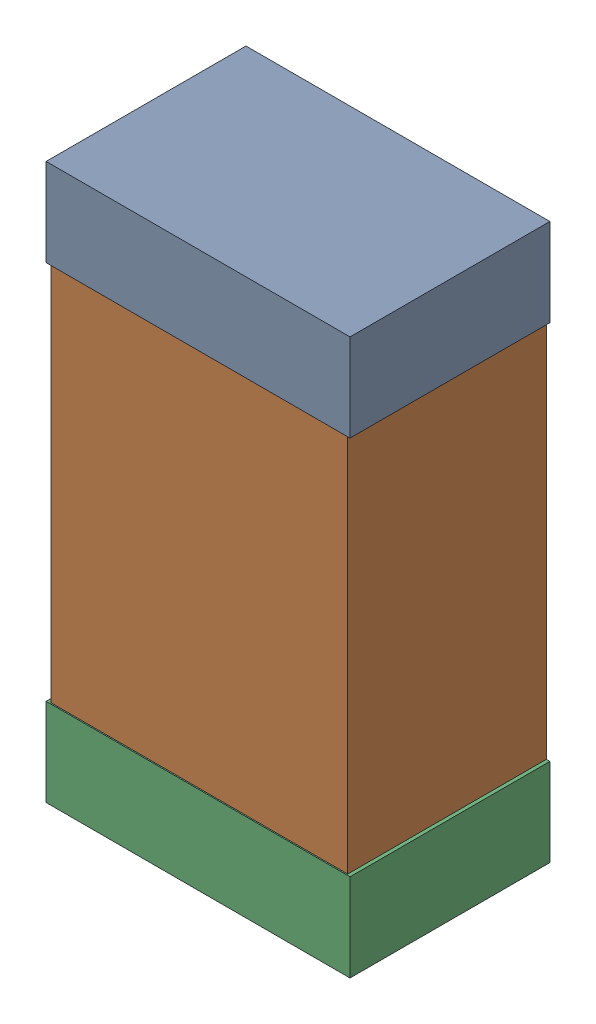
SolidWorks assembly 43.2kKanaloa_v2.0.0_Power, configuration Default. Lengths in mm.
Overall size (1.3 2.38 0.85).
6 component instances, 2 part files, 0 mates.
Components (placement in the parent):
- 330415056-1: 330415056 [Default] at (129.3608 95.3844 0) size (1.3 0.38 0.85)
  - Extruded_2-1: Extruded_2 [Default] at origin size (1.3 0.38 0.85)
- 334787376-1: 334787376 [Default] at (129.3608 94.3844 0) size (1.27 2.2 0.85)
  - Extruded_16-1: Extruded_16 [Default] at origin size (1.27 2.2 0.85)
- 330415056-2: 330415056 [Default] at (129.3608 93.3844 0) size (1.3 0.38 0.85)
  - Extruded_2-1: Extruded_2 [Default] at origin size (1.3 0.38 0.85)
